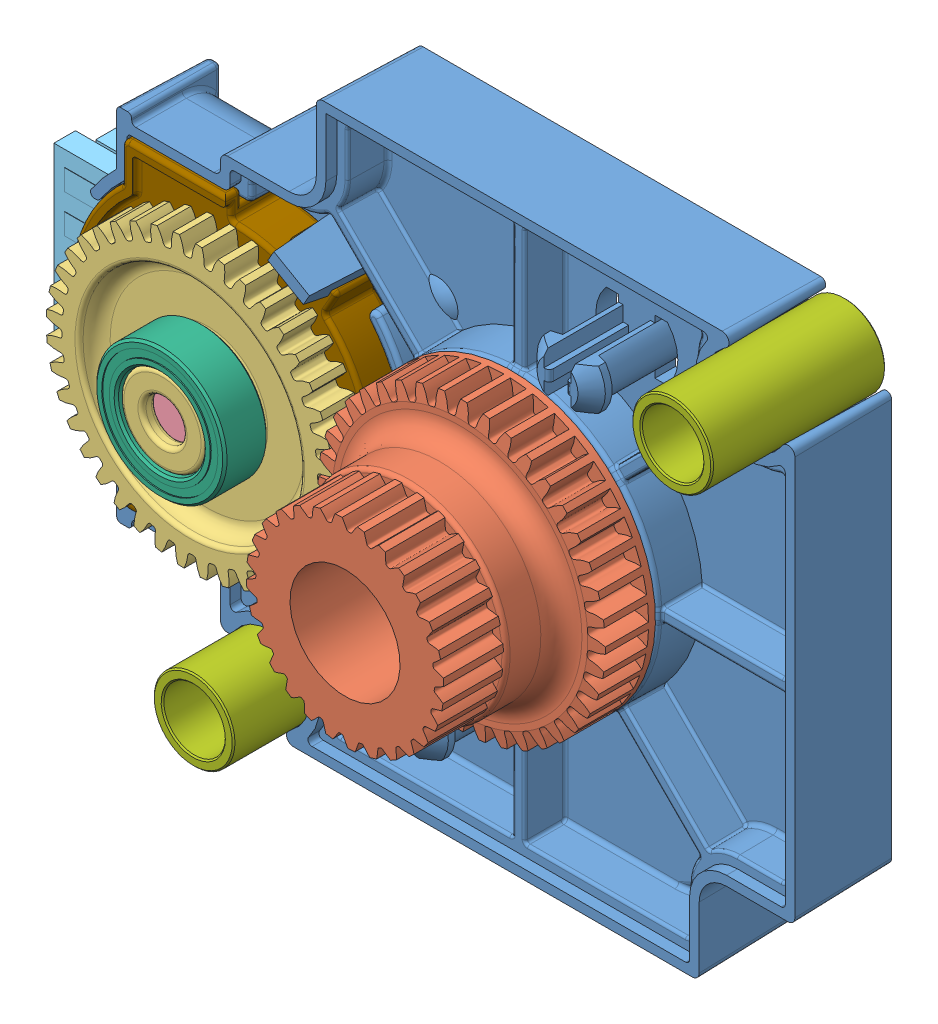
SolidWorks assembly VersaPlanetary_Integrated_Encoder_217-5046ELEVATOR, configuration Default. Lengths in mm.
Overall size (58.21 43.13 22.65).
11 component instances, 10 part files, 0 mates.
Components (placement in the parent):
- 217-4783-001 Rev3-1: 217-4783-001 Rev3 [Default] at (0 0 2.75) (suppressed, hidden)
- 217-4783-002 Rev7_Sealed Config-1: 217-4783-002 Rev7_Sealed Config [Default] at (0 0 -7.2) x (0 1 0) z (0 0 1) size (42 51.56 9.32)
- 217-4783-005 Rev7_40t_spur_REF_14deg-1: 217-4783-005 Rev7_40t_spur_REF_14deg [Default] at (0 0 5.95) x (0.660339 0.750968 0) z (0 0 1) size (21.16 21.1 17.1)
- 217-4783-004 Rev2_40t_spur_REF_14deg-1: 217-4783-004 Rev2_40t_spur_REF_14deg [Default] at (-20.05 0 5.2) x (-0.718289 0.695745 0) z (0 0 1) size (21.07 21.07 4.88)
- 217-4783-008 Rev2-1: 217-4783-008 Rev2 [Default] at (-20.05 0 2.2) x (0.307149 -0.951661 0) z (0.951661 0.307149 0) size (5 4 5)
- PCBA Rev3-1: PCBA Rev3 [Default] at (-20.05 0 -2.1252) x (0 1 0) z (-1 0 0) size (15.93 10.15 24.58)
- 217-2788-001 Rev3_57155K375-1: 217-2788-001 Rev3_57155K375 [Default] at (-20.05 0 3.8125) x (-0.99574 0.092202 0) z (0 0 1) size (9.53 9.53 3.17)
- 217-4783-006 Rev3-1: 217-4783-006 Rev3 [Default] at (17.5 17.5 -0.85) x (-0.867641 0.497191 0) z (0 0 1) size (5.9 5.9 12.7)
- 217-4783-006 Rev3-2: 217-4783-006 Rev3 [Default] at (-17.5 -17.5 -0.85) x (0.825154 -0.564908 0) z (0 0 1) size (5.9 5.9 12.7)
- 217-4783-007 Rev1-1: 217-4783-007 Rev1 [Default] at (-16.45 0 -5.2) x (0 1 0) z (0 0 1) size (6 10.71 3.56)
- 217-4783-003 Rev4-1: 217-4783-003 Rev4 [Default] at (-20.05 0 -1.02) x (0 1 0) z (0 0 1) size (23.4 21.71 4.21)
